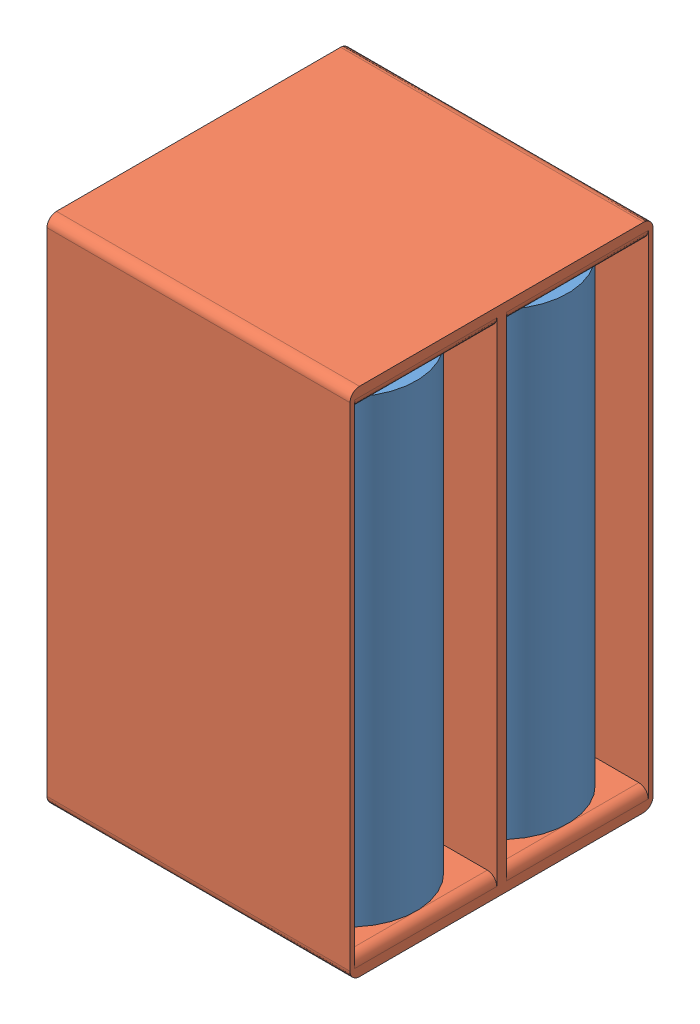
SolidWorks assembly BatteryPack, configuration Default. Lengths in mm.
Overall size (32 54 32).
5 component instances, 2 part files, 12 mates.
Components (placement in the parent):
- Battery-1: Battery [Default] at (2.3118 6.4867 42.8537) size (14 49.5 14)
- BatteryHolder-1: BatteryHolder [Default] at (-5.6882 31.4967 66.8537) x (0 -1 0) z (1 0 0) size (54 32 32)
- Battery-2: Battery [Default] at (-13.6882 6.4867 58.8537) x (-1 0 0) z (0 0 -1) size (14 49.5 14)
- Battery-3: Battery [Default] at (2.3118 6.4867 58.8537) size (14 49.5 14)
- Battery-4: Battery [Default] at (-13.6882 6.4867 42.8537) x (0 0 1) z (-1 0 0) size (14 49.5 14)
Mates (geometry in assembly coordinates):
- Concentric1: concentric anti-aligned: cylinder of Battery-1 through (2.3118 54.9867 42.8537) axis (0 -1 0) radius 7; cylinder of BatteryHolder-1 through (2.3118 6.4967 42.8537) axis (0 1 0) radius 7.5
- Concentric2: concentric anti-aligned: cylinder of BatteryHolder-1 through (2.3118 6.4967 58.8537) axis (0 1 0) radius 7.5; cylinder of Battery-3 through (2.3118 54.9867 58.8537) axis (0 -1 0) radius 7
- Coincident3: coincident anti-aligned: plane of BatteryHolder-1 through (2.3118 6.4967 58.8537) normal (0 1 0); plane of Battery-3 through (2.3118 6.4967 58.8537) normal (0 -1 0)
- Coincident4: coincident anti-aligned: plane of Battery-1 through (2.3118 6.4967 42.8537) normal (0 -1 0); plane of BatteryHolder-1 through (2.3118 6.4967 42.8537) normal (0 1 0)
- Concentric3: concentric anti-aligned: cylinder of BatteryHolder-1 through (-13.6882 6.4967 58.8537) axis (0 1 0) radius 7.5; cylinder of Battery-2 through (-13.6882 54.9867 58.8537) axis (0 -1 0) radius 7
- Coincident6: coincident anti-aligned: plane of BatteryHolder-1 through (-13.6882 6.4967 58.8537) normal (0 1 0); plane of Battery-2 through (-13.6882 6.4967 58.8537) normal (0 -1 0)
- Concentric4: concentric anti-aligned: cylinder of BatteryHolder-1 through (-13.6882 6.4967 42.8537) axis (0 1 0) radius 7.5; cylinder of Battery-4 through (-13.6882 54.9867 42.8537) axis (0 -1 0) radius 7
- Coincident7: coincident anti-aligned: plane of BatteryHolder-1 through (-13.6882 6.4967 42.8537) normal (0 1 0); plane of Battery-4 through (-13.6882 6.4967 42.8537) normal (0 -1 0)
- Parallel1: parallel aligned: plane of Battery-4 through (-13.6882 6.4867 42.8537) normal (0 0 1); plane of assembly through (0 0 0) normal (0 0 1)
- Parallel2: parallel aligned: plane of Battery-3 through (2.3118 6.4867 58.8537) normal (0 0 1); plane of assembly through (0 0 0) normal (0 0 1)
- Parallel3: parallel anti-aligned: plane of Battery-2 through (-13.6882 6.4867 58.8537) normal (0 0 -1); plane of assembly through (0 0 0) normal (0 0 1)
- Parallel4: parallel aligned: plane of BatteryHolder-1 through (-5.6882 31.4967 66.8537) normal (1 0 0); plane of assembly through (0 0 0) normal (1 0 0)
